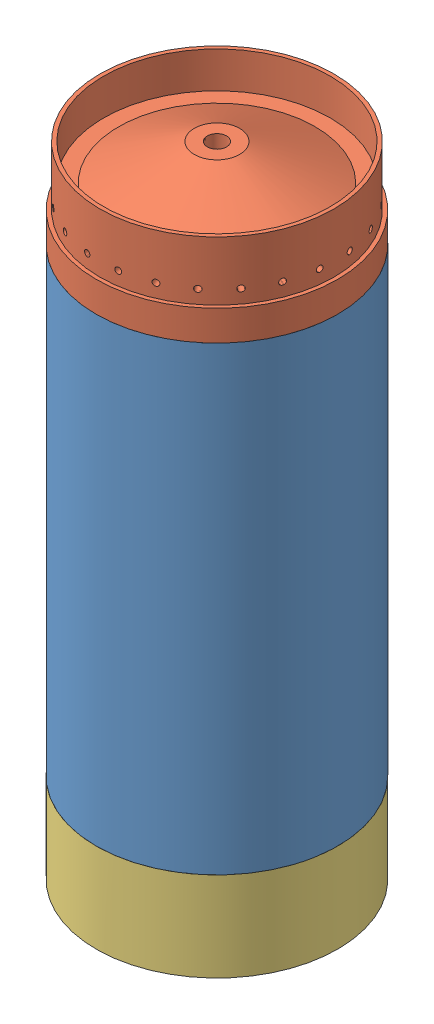
SolidWorks assembly FuelTank, configuration Default. Lengths in mm.
Overall size (287.14 625.6 287.14).
3 component instances, 3 part files, 6 mates.
Components (placement in the parent):
- FuelTankCylinder-1: FuelTankCylinder [Default] at (0 75.0887 0) x (0 1 0) z (-0.969773 0 -0.244009) size (387.35 203.2 203.2)
- IT-B-Bulkhead-1: IT-B-Bulkhead [Default] at (36.4095 499.9831 9.1612) x (0.244009 0 -0.969773) z (0.969773 0 0.244009) size (203.2 135.82 203.2)
- LT-B-BULKHEADv4-1: LT-B-BULKHEADv4 [Default] at (25.4703 37.5444 27.5834) x (-0.734689 0 0.678405) z (0.678405 0 0.734689) size (203.2 190.5 203.2)
Mates (geometry in assembly coordinates):
- Coincident1: coincident anti-aligned: plane of LT-B-BULKHEADv4-1 through (0 0 0) normal (0 -1 0)
- Concentric2: concentric aligned: circle of FuelTankCylinder-1; circle of LT-B-BULKHEADv4-1
- Coincident4: coincident anti-aligned: plane of FuelTankCylinder-1 through (0 75.0887 0) normal (0 -1 0); plane of LT-B-BULKHEADv4-1 through (0 75.0887 0) normal (0 1 0)
- Concentric3: concentric anti-aligned: circle of FuelTankCylinder-1; circle of IT-B-Bulkhead-1
- Coincident6: coincident anti-aligned: plane of FuelTankCylinder-1 through (0 462.4388 0) normal (0 1 0); plane of IT-B-Bulkhead-1 through (0 462.4388 0) normal (0 -1 0)
- Concentric4: concentric aligned: cylinder of LT-B-BULKHEADv4-1 through (0 75.0887 0) axis (0 1 0) radius 8.255
